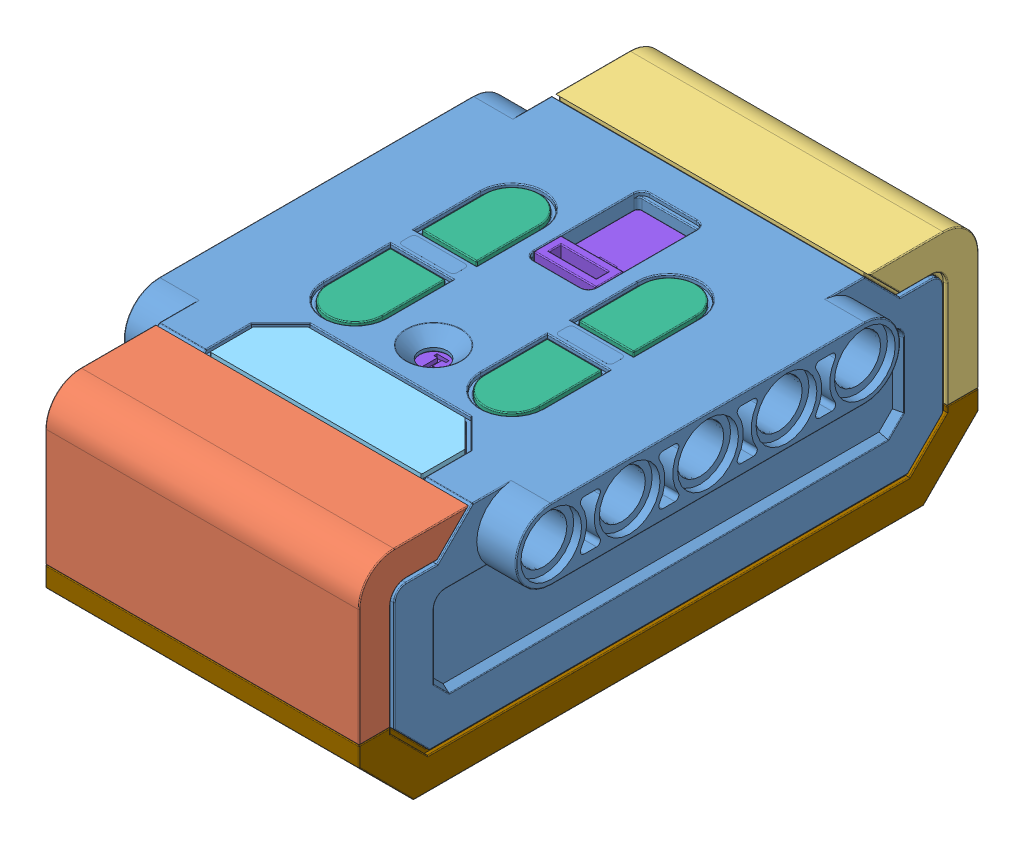
SolidWorks assembly 72156, configuration Default. Lengths in mm.
Overall size (40 23.23 63.21).
18 component instances, 9 part files, 0 mates.
Components (placement in the parent):
- 72156.stp-1: 72156.stp [Default] at origin size (40 23.23 63.21)
  - 76607c01.stp-1: 76607c01.stp [Default] at origin size (40 19.88 63.2)
    - 76607p01-White.stp-1: 76607p01-White.stp [Default] at origin size (40 19.62 56)
    - 11235-TransBlackIRLens.stp-1: 11235-TransBlackIRLens.stp [Default] at (0 -1.2 26.8) x (-1 0 0) z (0 0 -1) size (32 15.6 11.2)
    - 11235-LtBluishGray.stp-1: 11235-LtBluishGray.stp [Default] at (0 -1.2 -26.8) size (32 15.6 11.2)
    - 76608-White.stp-1: 76608-White.stp [Default] at (0 -8.8 0) size (28.8 18.26 60.8)
    - 11236-LtBluishGray.stp-1: 11236-LtBluishGray.stp [Default] at (0 2.8 15.6) x (1 0 0) z (0 0 -1) size (21.6 1.6 7.2)
    - 76610-LtBluishGray.stp-1: 76610-LtBluishGray.stp [Default] at (-8 2.8 -8) x (-1 0 0) z (0 0 -1) size (5.6 1.6 9.2)
    - 76610-LtBluishGray.stp-2: 76610-LtBluishGray.stp [Default] at (-8 2.8 8) size (5.6 1.6 9.2)
    - 76610-LtBluishGray.stp-3: 76610-LtBluishGray.stp [Default] at (8 2.8 -8) x (-1 0 0) z (0 0 -1) size (5.6 1.6 9.2)
    - 76610-LtBluishGray.stp-4: 76610-LtBluishGray.stp [Default] at (8 2.8 8) size (5.6 1.6 9.2)
    - u9013-Black.stp-1: u9013-Black.stp [Default] at (-12.4 -10 23.2) x (1 0 0) z (0 0 -1) size (4.01 6.01 4.01)
    - u9013-Black.stp-2: u9013-Black.stp [Default] at (12.4 -10 23.2) x (1 0 0) z (0 0 -1) size (4.01 6.01 4.01)
    - u9013-Black.stp-3: u9013-Black.stp [Default] at (-12.4 -10 -23.2) x (1 0 0) z (0 0 -1) size (4.01 6.01 4.01)
    - u9013-Black.stp-4: u9013-Black.stp [Default] at (12.4 -10 -23.2) x (1 0 0) z (0 0 -1) size (4.01 6.01 4.01)
  - 11237-Red.stp-1: 11237-Red.stp [Default] at (0 2 -0.2) size (8 2.8 36)
  - u9013-Black.stp-1: u9013-Black.stp [Default] at (0 -13.2 -28) x (1 0 0) z (0 0 -1) size (4.01 6.01 4.01)
  - 76609-LtBluishGray.stp-1: 76609-LtBluishGray.stp [Default] at (0 -16 0) x (0 0 -1) z (1 0 0) size (63.21 11.21 32.01)
